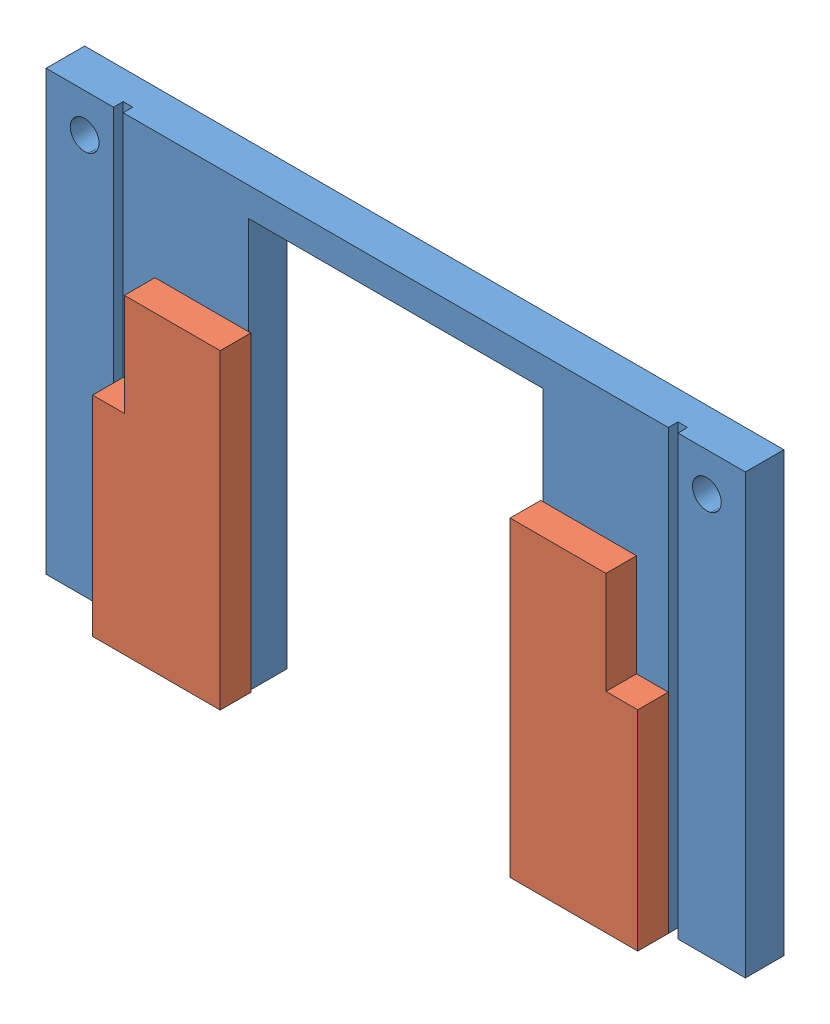
SolidWorks assembly food_cover_assem, configuration lever_in_use. Lengths in mm.
Overall size (72.6 45.5 7.18).
3 component instances, 2 part files, 6 mates.
Components (placement in the parent):
- food_cover_mount-1: food_cover_mount [in_use] at (5.5427 27.7298 65.2964) size (72.6 45.5 4)
- food_cover-1: food_cover [half] at (13.5427 27.7298 69.2964)
- food_cover-2: food_cover [half] at (70.1427 27.7298 72.4714) x (-1 0 0) z (0 0 -1)
Mates (geometry in assembly coordinates):
- Coincident1: coincident anti-aligned: plane of food_cover_mount-1 through (5.5427 27.7298 69.2964) normal (0 0 1); plane of food_cover-1 through (13.5427 27.7298 69.2964) normal (0 0 -1)
- Coincident2: coincident aligned: plane of food_cover_mount-1 through (13.5427 27.7298 68.2964) normal (-1 0 0); plane of food_cover-1 through (13.5427 27.7298 72.4714) normal (-1 0 0)
- Coincident3: coincident aligned: plane of food_cover_mount-1 through (5.5427 27.7298 69.2964) normal (0 -1 0); plane of food_cover-1 through (13.5427 27.7298 72.4714) normal (0 -1 0)
- Coincident4: coincident aligned: plane of food_cover_mount-1 through (5.5427 27.7298 69.2964) normal (0 -1 0); plane of food_cover-2 through (70.1427 27.7298 69.2964) normal (0 -1 0)
- Coincident5: coincident anti-aligned: plane of food_cover_mount-1 through (5.5427 27.7298 69.2964) normal (0 0 1); plane of food_cover-2 through (70.1427 27.7298 69.2964) normal (0 0 -1)
- Coincident6: coincident aligned: plane of food_cover_mount-1 through (70.1427 27.7298 68.2964) normal (1 0 0); plane of food_cover-2 through (70.1427 27.7298 69.2964) normal (1 0 0)
